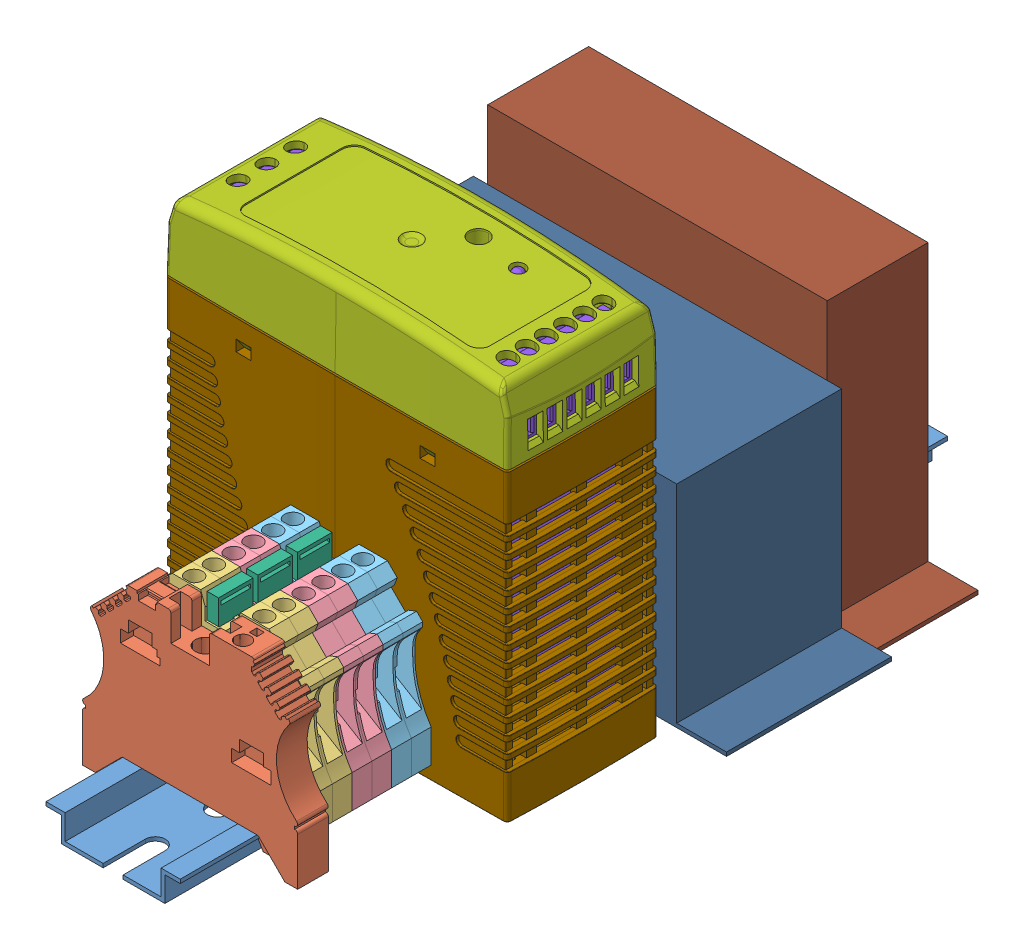
SolidWorks assembly USB-Hubs, configuration Standard. Lengths in mm.
Overall size (122 108.8 200).
18 component instances, 11 part files, 46 mates.
Components (placement in the parent):
- Hutschiene-1: Hutschiene [200] at (-17.5 -7.5 -200) size (35 7.5 200)
- WEW_35_2-1: WEW_35_2 [Standard] at (-45.49 -7 -28) x (0 0 1) z (0 1 0) size (8 56.1 46.5)
- UT_2.5-1: UT_2.5 [Standard] at (-48.6989 10.6178 -28) x (0.992546 -0.121869 0) z (0 0 1) size (49.27 50.96 5.15)
- UT_2.5-2: UT_2.5 [Standard] at (-48.6989 10.6178 -33.15) x (0.992546 -0.121869 0) z (0 0 1) size (49.27 50.96 5.15)
- UT_2.5_BU-1: UT_2.5_BU [Standard] at (-48.6989 10.6178 -38.3) x (0.992546 -0.121869 0) z (0 0 1) size (49.27 50.96 5.15)
- UT_2.5_BU-2: UT_2.5_BU [Standard] at (-48.6989 10.6178 -43.45) x (0.992546 -0.121869 0) z (0 0 1) size (49.27 50.96 5.15)
- UT_2.5_PE-1: UT_2.5_PE [Standard] at (-48.6989 10.6178 -48.6) x (0.992546 -0.121869 0) z (0 0 1) size (49.27 50.96 5.15)
- UT_2.5_PE-2: UT_2.5_PE [Standard] at (-48.6989 10.6178 -53.75) x (0.992546 -0.121869 0) z (0 0 1) size (49.27 50.96 5.15)
- FBS_2-5-1: FBS_2-5 [Standard] at (-24.1072 49.175 -86.835) size (3 22.98 9)
- FBS_2-5-2: FBS_2-5 [Standard] at (-24.1072 49.175 -97.135) size (3 22.98 9)
- FBS_2-5-3: FBS_2-5 [Standard] at (-24.1072 49.175 -107.435) size (3 22.98 9)
- MDR-40&60-1: MDR-40&60 [Standard] at (-18.5044 35.1498 -79.0396) x (0 0 -1) z (0 1 0) size (40 91.72 100.24)
  - Skin_Group1-1: Skin_Group1 [Standard] at origin size (40 89.9 28.74)
  - 3P-CONECT-1: 3P-CONECT [Standard] at (-7.6496 -37.3548 41.6035) x (-1 0 0) z (0 1 0) size (34.1 93.54 85.1)
  - Skin_Group1.1-1: Skin_Group1.1 [Standard] at origin size (40 91.72 79.26)
- EX-1178-1: EX-1178 [Standard] at (-17.5 0 -120.4) size (122 57 43)
- EX-1188HMS-2-1: EX-1188HMS-2 [Standard] at (-17.5 0 -155.05) size (114.5 75 26.3)
- WEW_35_2-2: WEW_35_2 [Standard] at (10.61 -7 -168.2) x (0 0 -1) z (0 1 0) size (8 56.1 46.5)
Mates (geometry in assembly coordinates):
- Deckungsgleich1: coincident aligned: plane of Hutschiene-1 through (-17.5 -7.5 0) normal (0 0 1); plane of assembly through (0 0 0) normal (0 0 1)
- Deckungsgleich2: coincident aligned: plane of Hutschiene-1 through (-30 0 0) normal (0 1 0); plane of assembly through (0 0 0) normal (0 1 0)
- Deckungsgleich3: coincident aligned: plane of Hutschiene-1 through (0 -1 0) normal (1 0 0); plane of assembly through (0 0 0) normal (1 0 0)
- Deckungsgleich4: coincident anti-aligned: plane of Hutschiene-1 through (-30 0 0) normal (0 1 0); plane of WEW_35_2-1 through (0.26 0 -20) normal (0 -1 0)
- Parallel1: parallel aligned: plane of Hutschiene-1 through (0 -1 0) normal (1 0 0); plane of WEW_35_2-1 through (10.61 -7 -20) normal (1 0 0)
- Abstand1: distance = 20 mm aligned: plane of WEW_35_2-1 through (-17.44 0 -20) normal (0 0 1); plane of Hutschiene-1 through (-17.5 -7.5 0) normal (0 0 1)
- Tangential2: tangent anti-aligned: plane of Hutschiene-1 through (-35 0 0) normal (-1 0 0); cylinder of WEW_35_2-1 through (-37 -1.4 -24) axis (0 0 1) radius 2
- Deckungsgleich8: coincident anti-aligned: plane of WEW_35_2-1 through (-17.44 0 -28) normal (0 0 -1); plane of UT_2.5-1 through (0 0 -28) normal (0 0 1)
- Deckungsgleich9: coincident anti-aligned: plane of UT_2.5-1 through (0 0 -33.15) normal (0 0 -1); plane of UT_2.5-2 through (0 0 -33.15) normal (0 0 1)
- Deckungsgleich10: coincident anti-aligned: plane of Hutschiene-1 through (-30 0 0) normal (0 1 0); plane of UT_2.5-1 through (-7.7 0 -28) normal (0 -1 0)
- Deckungsgleich11: coincident anti-aligned: plane of Hutschiene-1 through (-30 0 0) normal (0 1 0); plane of UT_2.5-2 through (-7.7 0 -33.15) normal (0 -1 0)
- Deckungsgleich12: coincident anti-aligned: plane of Hutschiene-1 through (0 -1 0) normal (1 0 0); plane of UT_2.5-1 through (0 -1.1 -28) normal (-1 0 0)
- Deckungsgleich13: coincident anti-aligned: plane of Hutschiene-1 through (0 -1 0) normal (1 0 0); plane of UT_2.5-2 through (0 -1.1 -33.15) normal (-1 0 0)
- Deckungsgleich14: coincident anti-aligned: plane of UT_2.5-2 through (0 0 -38.3) normal (0 0 -1); plane of UT_2.5_BU-1 through (0 0 -38.3) normal (0 0 1)
- Deckungsgleich15: coincident anti-aligned: plane of UT_2.5_BU-1 through (0 0 -43.45) normal (0 0 -1); plane of UT_2.5_BU-2 through (0 0 -43.45) normal (0 0 1)
- Deckungsgleich16: coincident anti-aligned: plane of Hutschiene-1 through (-30 0 0) normal (0 1 0); plane of UT_2.5_BU-2 through (-7.7 0 -43.45) normal (0 -1 0)
- Deckungsgleich17: coincident anti-aligned: plane of Hutschiene-1 through (-30 0 0) normal (0 1 0); plane of UT_2.5_BU-1 through (-7.7 0 -38.3) normal (0 -1 0)
- Deckungsgleich18: coincident anti-aligned: plane of Hutschiene-1 through (0 -1 0) normal (1 0 0); plane of UT_2.5_BU-1 through (0 -1.1 -38.3) normal (-1 0 0)
- Deckungsgleich19: coincident anti-aligned: plane of Hutschiene-1 through (0 -1 0) normal (1 0 0); plane of UT_2.5_BU-2 through (0 -1.1 -43.45) normal (-1 0 0)
- Deckungsgleich20: coincident anti-aligned: plane of UT_2.5_BU-2 through (0 0 -48.6) normal (0 0 -1); plane of UT_2.5_PE-1 through (0 0 -48.6) normal (0 0 1)
- Deckungsgleich21: coincident anti-aligned: plane of UT_2.5_PE-1 through (0 0 -53.75) normal (0 0 -1); plane of UT_2.5_PE-2 through (0 0 -53.75) normal (0 0 1)
- Deckungsgleich22: coincident anti-aligned: plane of Hutschiene-1 through (-30 0 0) normal (0 1 0); plane of UT_2.5_PE-1 through (-7.7 0 -48.6) normal (0 -1 0)
- Deckungsgleich23: coincident anti-aligned: plane of Hutschiene-1 through (-30 0 0) normal (0 1 0); plane of UT_2.5_PE-2 through (-7.7 0 -53.75) normal (0 -1 0)
- Deckungsgleich24: coincident anti-aligned: plane of Hutschiene-1 through (0 -1 0) normal (1 0 0); plane of UT_2.5_PE-1 through (0 -1.1 -48.6) normal (-1 0 0)
- Deckungsgleich25: coincident anti-aligned: plane of Hutschiene-1 through (0 -1 0) normal (1 0 0); plane of UT_2.5_PE-2 through (0 -1.1 -53.75) normal (-1 0 0)
- Deckungsgleich26: coincident aligned: plane of UT_2.5-1 through (-30.1 40 -28) normal (0 1 0); plane of FBS_2-5-1 through (-18.5 40 -7.975) normal (0 1 0)
- Deckungsgleich27: coincident aligned: plane of UT_2.5_BU-1 through (-30.1 40 -38.3) normal (0 1 0); plane of FBS_2-5-2 through (-18.5 40 -18.275) normal (0 1 0)
- Deckungsgleich28: coincident aligned: plane of UT_2.5_PE-1 through (-30.1 40 -48.6) normal (0 1 0); plane of FBS_2-5-3 through (-18.5 40 -28.575) normal (0 1 0)
- Deckungsgleich29: coincident anti-aligned: plane of UT_2.5-1 through (-18.35 21.85 -28.475) normal (0 0 -1); plane of FBS_2-5-1 through (-18.5 39.7 -28.475) normal (0 0 1)
- Deckungsgleich30: coincident anti-aligned: plane of UT_2.5_BU-1 through (-18.35 21.85 -38.775) normal (0 0 -1); plane of FBS_2-5-2 through (-18.5 39.7 -38.775) normal (0 0 1)
- Deckungsgleich31: coincident anti-aligned: plane of UT_2.5_PE-1 through (-18.35 21.85 -49.075) normal (0 0 -1); plane of FBS_2-5-3 through (-18.5 39.7 -49.075) normal (0 0 1)
- Deckungsgleich32: coincident anti-aligned: plane of UT_2.5-1 through (-21.5 36.703 -28) normal (1 0 0); plane of FBS_2-5-1 through (-21.5 41.9423 -62.735) normal (-1 0 0)
- Deckungsgleich33: coincident anti-aligned: plane of UT_2.5_BU-1 through (-21.5 36.703 -38.3) normal (1 0 0); plane of FBS_2-5-2 through (-21.5 41.9423 -73.035) normal (-1 0 0)
- Deckungsgleich34: coincident anti-aligned: plane of UT_2.5_PE-1 through (-21.5 36.703 -48.6) normal (1 0 0); plane of FBS_2-5-3 through (-21.5 41.9423 -83.335) normal (-1 0 0)
- Deckungsgleich35: coincident anti-aligned: plane of Hutschiene-1 through (-30 0 0) normal (0 1 0); plane of MDR-40&60-1/Skin_Group1.1-1 through (-62.0045 0 -99.4001) normal (0 -1 0)
- Deckungsgleich36: coincident anti-aligned: plane of Hutschiene-1 through (-35 0 0) normal (-1 0 0); plane of MDR-40&60-1/Skin_Group1.1-1 through (-35 0.0063 -81.6859) normal (1 0 0)
- Tangential3: tangent anti-aligned: plane of UT_2.5_PE-2 through (0 0 -58.9) normal (0 0 -1); cylinder of MDR-40&60-1/Skin_Group1.1-1 through (-18.5544 -4.3965 -3426.5541) axis (0 1 0) radius 3367.6541
- Tangential4: tangent anti-aligned: cylinder of MDR-40&60-1/Skin_Group1.1-1 through (-18.5544 -4.3965 3268.7541) axis (0 1 0) radius 3367.6541; plane of EX-1178-1 through (-78.5 55 -98.9) normal (0 0 1)
- Deckungsgleich37: coincident anti-aligned: plane of Hutschiene-1 through (0 0 0) normal (0 1 0); plane of EX-1178-1 through (-17.5 0 -120.4) normal (0 -1 0)
- Deckungsgleich38: coincident anti-aligned: plane of Hutschiene-1 through (-35 0 0) normal (-1 0 0); plane of EX-1178-1 through (-35 -1 -141.9) normal (1 0 0)
- Deckungsgleich39: coincident anti-aligned: plane of EX-1178-1 through (-78.5 55 -141.9) normal (0 0 -1); plane of EX-1188HMS-2-1 through (-74.75 73 -141.9) normal (0 0 1)
- Deckungsgleich40: coincident anti-aligned: plane of Hutschiene-1 through (-30 0 0) normal (0 1 0); plane of EX-1188HMS-2-1 through (-17.5 0 -155.05) normal (0 -1 0)
- Deckungsgleich41: coincident anti-aligned: plane of Hutschiene-1 through (-35 0 0) normal (-1 0 0); plane of EX-1188HMS-2-1 through (-35 0 -168.2) normal (1 0 0)
- Deckungsgleich42: coincident anti-aligned: plane of Hutschiene-1 through (-30 0 0) normal (0 1 0); plane of WEW_35_2-2 through (-35.14 0 -176.2) normal (0 -1 0)
- Deckungsgleich43: coincident aligned: plane of WEW_35_2-1 through (-45.49 -7 -20) normal (-1 0 0); plane of WEW_35_2-2 through (-45.49 -7 -176.2) normal (-1 0 0)
- Deckungsgleich44: coincident anti-aligned: plane of WEW_35_2-2 through (-17.44 0 -168.2) normal (0 0 1); plane of EX-1188HMS-2-1 through (-74.75 73 -168.2) normal (0 0 -1)
